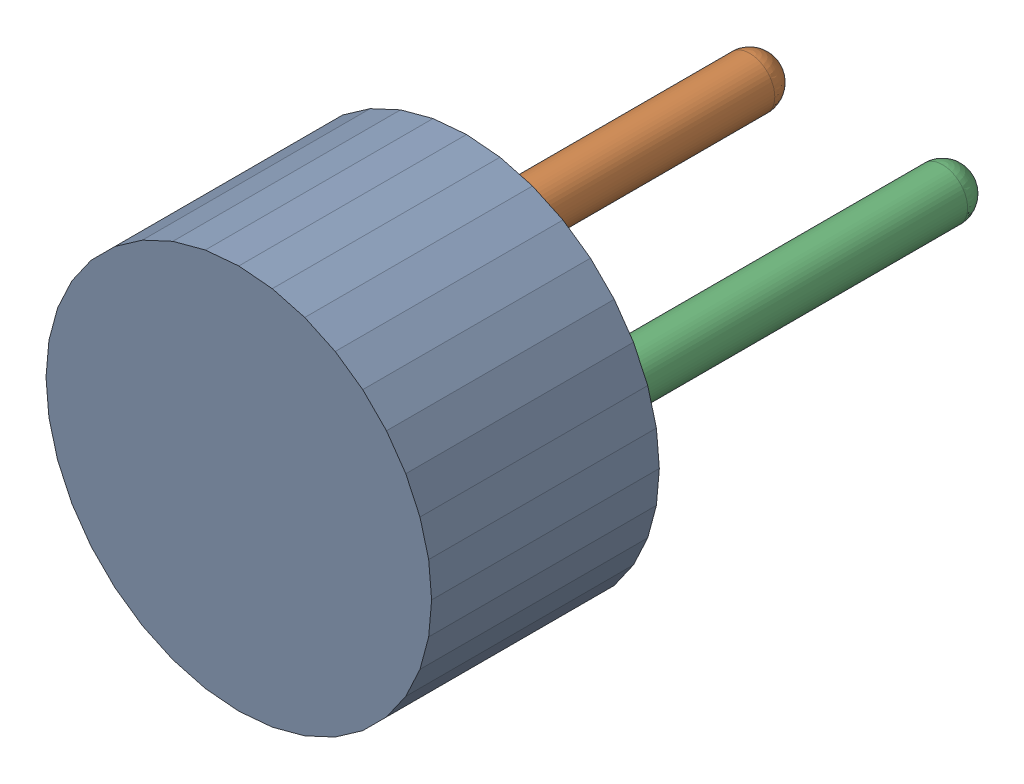
SolidWorks assembly Open CASCADE STEP translator 6.8 1.19.1, configuration Défaut. Lengths in mm.
Overall size (5.08 5.08 8.33).
3 component instances, 3 part files, 0 mates.
Components (placement in the parent):
- Body_1_10-1: Body_1_10 [Défaut] at origin size (5.08 5.08 3)
- Pin_1_7-1: Pin_1_7 [Défaut] x (0 -1 0) z (0 0 1) size (0.66 0.66 7.16)
- Pin_2_7-1: Pin_2_7 [Défaut] at (2.54 2.54 0) x (0 -1 0) z (0 0 1) size (0.66 0.66 7.16)
